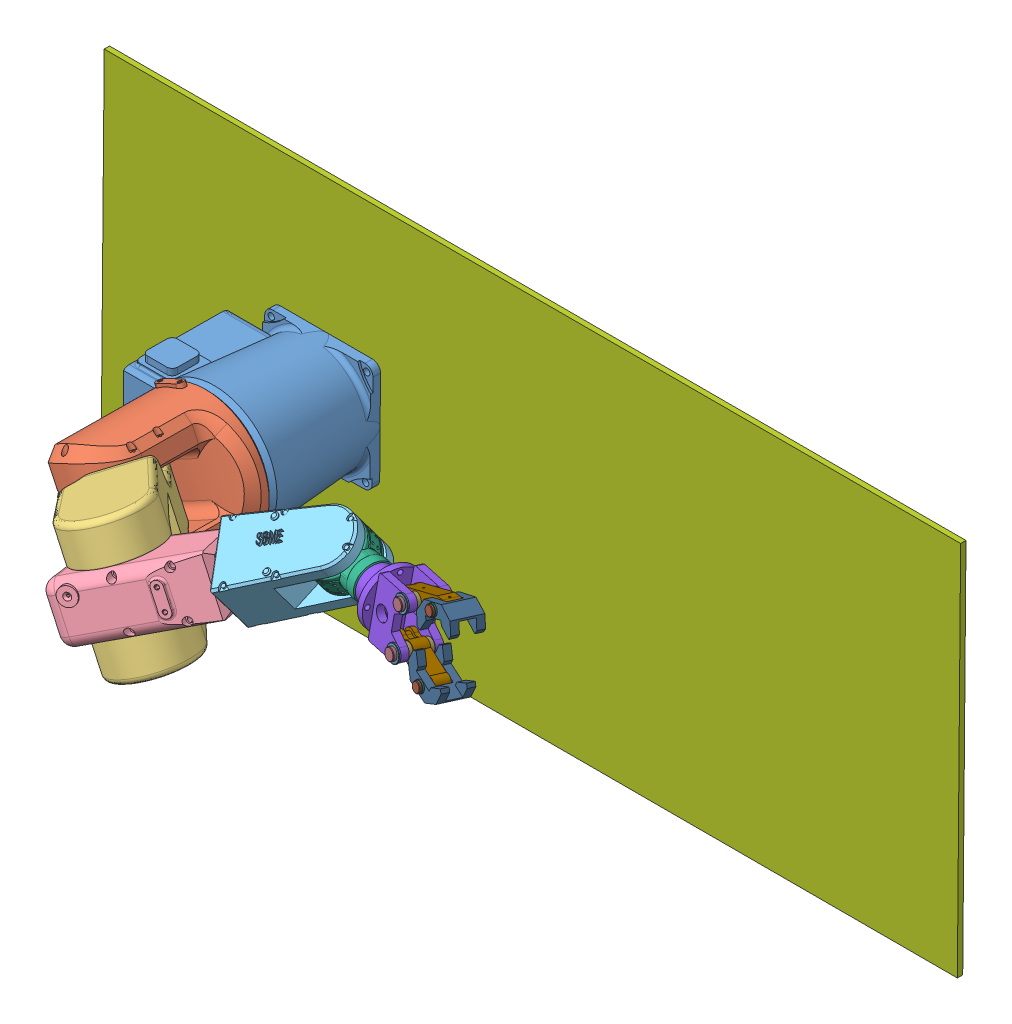
SolidWorks assembly 装配体1, configuration 默认. Lengths in mm.
Overall size (1600 704.24 739.49).
25 component instances, 15 part files, 16 mates.
Components (placement in the parent):
- 0-1: 0 [默认] at (0 189.2873 -190.9464) x (1 0 0) z (0 -0.999962 0.008727) size (1102.73 385.61 236.5)
- 1-1: 1 [默认] at (0 191.2159 30.0452) x (-0.42745 0.904005 -0.007889) z (0.904039 0.427434 -0.00373) size (250 234.43 240.02)
- 2-1: 2 [默认] at (240.0095 308.0626 415.1132) x (-0.598725 -0.276542 0.7517) z (0.677358 0.326038 0.659458) size (155.97 235 500.03)
- 3-1: 3 [默认] at (389.0082 378.1065 368.2815) x (-0.835977 -0.391932 0.384099) z (-0.344135 -0.170778 -0.923258) size (250.18 103 166.59)
- 4-1: 4 [默认] at (527.1644 442.8785 304.804) x (0.835977 0.391932 -0.384099) z (-0.111573 0.806707 0.580324) size (240.41 124.2 113.23)
- 5-1: 5 [默认] at (527.0808 443.4835 305.2393) x (-0.166853 -0.590887 0.789311) z (-0.111573 0.806707 0.580324) size (145.31 190.05 95.56)
- 零件1^装配体1-1: 零件1^装配体1 [默认] at (0 189.2873 -190.9464) x (-1 0 0) z (0 -0.008727 -0.999962) size (1600 700 489.44) (virtual)
- joint7-1: joint7 [默认] at (605.4527 442.7824 321.2816) x (-0.196317 0.166265 0.966341) z (-0.979649 0.008763 -0.200529) size (105 164.84 211.36)
  - 14-1: 14 [默认] at origin size (105 105 164.01)
  - 18-1: 18 [默认] at (0 38.5 -107) x (0 0.344424 -0.938814) z (1 0 0) size (111.06 36.13 28)
  - 19-1: 19 [默认] at (0 69.5489 -159.698) x (0 0.330078 -0.943954) z (1 0 0) size (82.89 45 56.5)
  - 22-1: 22 [默认] at (35 59.1654 -163.3289) x (0 -0.811761 -0.583989) z (-1 0 0) size (18 18 66)
  - 24-1: 24 [默认] at (-21 38.5 -107) x (0 -0.533782 -0.845622) z (1 0 0) size (26 26 7)
  - 25-1: 25 [默认] at (44 38.5 -107) x (-1 0 0) z (0 -0.659078 -0.752075) size (82 21 21)
  - 24-2: 24 [默认] at (21 38.5 -107) x (0 -0.699829 -0.71431) z (-1 0 0) size (26 26 7)
  - 26-1: 26 [默认] at (26.3555 38.5 -107) x (0 -0.33616 0.941805) z (0 0.941805 0.33616) size (45 11.64 30)
  - 23-1: 23 [默认] at (28 59.1654 -163.3289) x (0 -0.043815 -0.99904) z (1 0 0) size (20 20 3)
  - 19-2: 19 [默认] at (0 -69.5489 -159.698) x (0 -0.330078 -0.943954) z (-1 0 0) size (82.89 45 56.5)
  - 18-2: 18 [默认] at (0 -38.5 -107) x (0 -0.344424 -0.938814) z (-1 0 0) size (111.06 36.13 28)
  - 22-2: 22 [默认] at (35 -59.1654 -163.3289) x (0 -0.811761 0.583989) z (-1 0 0) size (18 18 66)
  - 23-2: 23 [默认] at (31 -59.1654 -163.3289) x (0 0.043815 -0.99904) z (-1 0 0) size (20 20 3)
  - 25-2: 25 [默认] at (44 -38.5 -107) x (-1 0 0) z (0 -0.659078 0.752075) size (82 21 21)
  - 26-2: 26 [默认] at (26.3555 -38.5 -107) x (0 0.33616 0.941805) z (0 0.941805 -0.33616) size (45 11.64 30)
  - 24-4: 24 [默认] at (14 -38.5 -107) x (0 0.699829 -0.71431) z (1 0 0) size (26 26 7)
  - 24-5: 24 [默认] at (-14 -38.5 -107) x (0 0.533782 -0.845622) z (-1 0 0) size (26 26 7)
Mates (geometry in assembly coordinates):
- 同心1: concentric anti-aligned: circle of 0-1; cylinder of 1-1 through (0 191.4777 60.044) axis (0 -0.008727 -0.999962) radius 120
- 重合1: coincident anti-aligned: plane of 0-1 through (0 191.1984 28.0453) normal (0 0.008727 0.999962); plane of 1-1 through (0 191.1984 28.0453) normal (0 -0.008727 -0.999962)
- 同心3: concentric anti-aligned: cylinder of 1-1 through (-23.5098 242.3149 187.6053) axis (0.42745 -0.904005 0.007889) radius 50; cylinder of 2-1 through (50.2254 86.3741 188.9661) axis (-0.42745 0.904005 -0.007889) radius 77.5
- 重合2: coincident anti-aligned: plane of 1-1 through (0 191.2159 30.0452) normal (-0.42745 0.904005 -0.007889); plane of 2-1 through (240.0095 308.0626 415.1132) normal (0.42745 -0.904005 0.007889)
- 同心4: concentric aligned: circle of 2-1; circle of 3-1
- 同心7: concentric anti-aligned: circle of 4-1; circle of 5-1
- 重合5: coincident anti-aligned: plane of 4-1 through (524.2914 463.6512 319.7474) normal (0.111573 -0.806707 -0.580324); plane of 5-1 through (524.2914 463.6512 319.7474) normal (-0.111573 0.806707 0.580324)
- 在位1: in place: plane of assembly through (86.175 0 -86.175) normal (0 -1 0); plane of ? through (0 0 0) normal (0 -1 0); moOrthogonalPlaneRef_w of assembly through (86.175 0 -86.175) normal (0 -1 0); plane of ? through (0 0 0) normal (0 0 -1); plane of assembly through (86.175 0 -86.175) normal (0 -1 0); plane of ? through (0 0 0) normal (-1 0 0); plane of 0-1 through (86.175 275.459 -191.6984) normal (0 -0.008727 -0.999962); unknown of 零件1^装配体1-1
- 重合5: coincident aligned: plane of 0-1; plane of 零件1^装配体1-1
- 重合6: coincident aligned: moOrthogonalPlaneRef_w of 0-1; plane of 零件1^装配体1-1 through (0 189.2873 -190.9464) normal (0 0.999962 -0.008727)
- 重合7: coincident anti-aligned: moOrthogonalPlaneRef_w of 0-1 through (0 189.2873 -190.9464) normal (1 0 0); plane of 零件1^装配体1-1 through (0 189.2873 -190.9464) normal (-1 0 0)
- 重合6: coincident anti-aligned: plane of 2-1 through (240.0095 308.0626 415.1132) normal (0.42745 -0.904005 0.007889); plane of 3-1 through (389.0082 378.1065 368.2815) normal (-0.42745 0.904005 -0.007889)
- 同心8: concentric aligned: circle of 3-1; cylinder of 4-1 through (367.9834 368.2495 377.9416) axis (0.835977 0.391932 -0.384099) radius 39.035
- 重合7: coincident anti-aligned: plane of 3-1 through (350.429 414.7679 321.7241) normal (0.835977 0.391932 -0.384099); plane of 4-1 through (351.5822 446.5265 356.6404) normal (-0.835977 -0.391932 0.384099)
- 同心9: concentric aligned: cylinder of 5-1 through (585.8597 442.9577 317.271) axis (0.979649 -0.008763 0.200529) radius 34; cylinder of joint7-1/14-1 through (605.4527 442.7824 321.2816) axis (0.979649 -0.008763 0.200529) radius 26
- 重合8: coincident anti-aligned: plane of 5-1 through (605.4527 442.7824 321.2816) normal (0.979649 -0.008763 0.200529); plane of joint7-1/14-1 through (605.4527 442.7824 321.2816) normal (-0.979649 0.008763 -0.200529)
